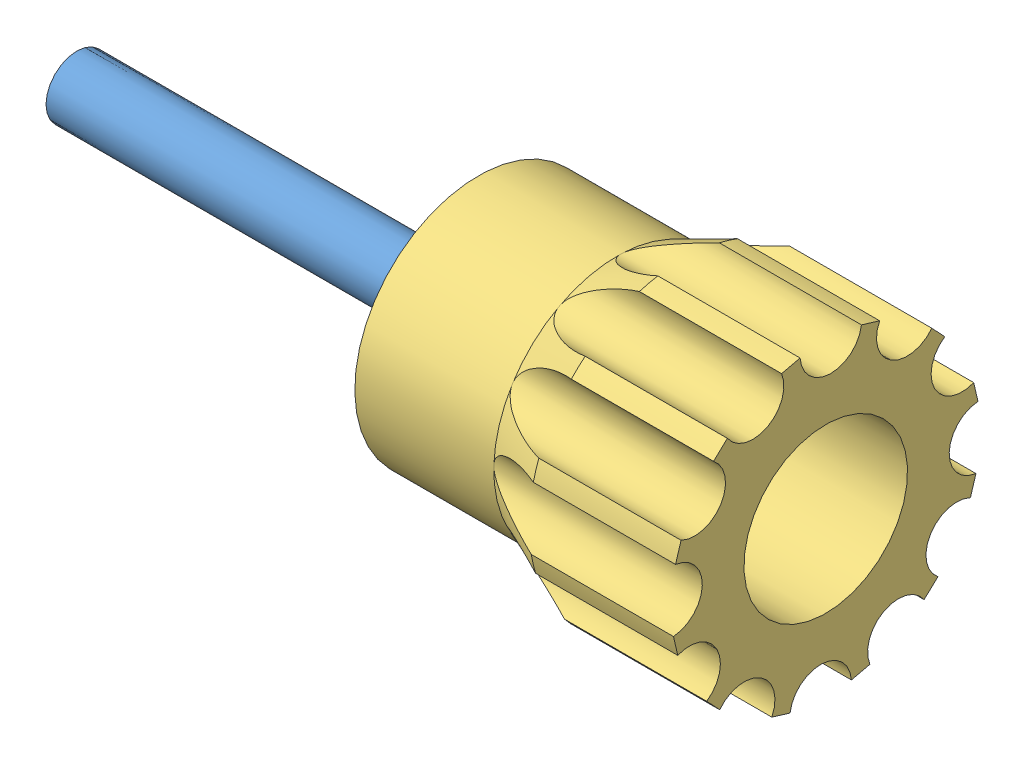
SolidWorks assembly 8-32 Finger Grip Assembly, configuration Default. Lengths in mm.
Overall size (48.5 23.33 23.33).
3 component instances, 3 part files, 4 mates.
Components (placement in the parent):
- 8-32 x 1,25inch-1: 8-32 x 1,25inch [Default] at (21.7967 15.93 23.3163) size (34.6 9.7 9.7)
- 8-32-1: 8-32 [Default] at (15.1467 15.93 23.3163) x (1 0 0) z (0 0.5 0.866025) size (3.15 8.55 9.87)
- 8-32 Finger Grip-3: 8-32 Finger Grip [Default] at (208.851 11.3533 54.7099) x (-1 0 0) z (0 0.128479 0.991712) size (22.5 20.83 20.83)
Mates (geometry in assembly coordinates):
- Coincident6: coincident anti-aligned: plane of 8-32 x 1,25inch-1 through (21.7967 15.93 23.3163) normal (-1 0 0); plane of 8-32 Finger Grip-3 through (21.7967 15.93 23.3163) normal (1 0 0)
- Concentric5: concentric aligned: cylinder of 8-32 x 1,25inch-1 through (-10.2033 15.93 23.3163) axis (1 0 0) radius 2; cylinder of 8-32 Finger Grip-3 through (11.7967 15.93 23.3163) axis (1 0 0) radius 2.125
- Concentric6: concentric aligned: cylinder of 8-32 x 1,25inch-1 through (-10.2033 15.93 23.3163) axis (1 0 0) radius 2; cylinder of 8-32-1 through (11.2967 15.93 23.3163) axis (1 0 0) radius 2
- Coincident7: coincident anti-aligned: plane of 8-32-1 through (18.2967 15.93 23.3163) normal (1 0 0); plane of 8-32 Finger Grip-3 through (18.2967 11.3533 54.7099) normal (-1 0 0)
